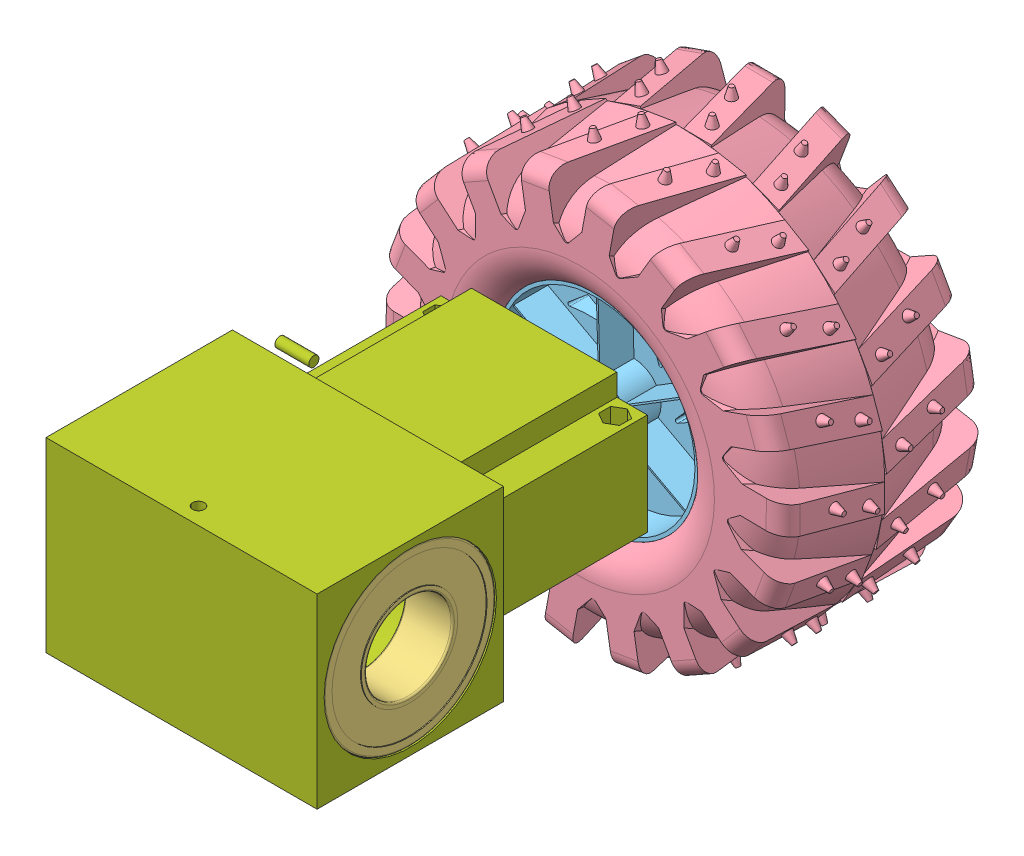
SolidWorks assembly Arm, configuration Default. Lengths in mm.
Overall size (177.35 260.67 181.49).
17 component instances, 13 part files, 22 mates.
Components (placement in the parent):
- Pololu_GearMotor_37Dmm-1: Pololu_GearMotor_37Dmm [Default] at (-21.9765 6.5818 -8.7754) x (0.802354 -0.596848 0.000047) z (-0.000059 0 1) size (51.49 51.49 82.3)
  - Pololu_ShaftGearMotor6mm-1: Pololu_ShaftGearMotor6mm [Default] at (9.8861 24.7007 16.6991) x (0.930815 0.36549 0) z (0 0 1) size (6 6 22)
  - Pololu_GearMotor_37Dmm-1: Pololu_GearMotor_37Dmm [Default] at (5.7082 30.3171 38.6991) x (-0.802354 -0.596848 0) z (0 0 -1) size (36.8 36.8 66.8)
- BallBearing16412RS-1: BallBearing16412RS [Default] at (40.4875 7.4102 -38.9392) x (-0.000059 0.14438 0.989522) z (-1 0 -0.000059) size (50.8 50.8 14.29)
- BallBearing16412RS-2: BallBearing16412RS [Default] at (-24.8068 -116.646 75.0398) x (-0.000012 0.977505 0.210913) z (-1 0 -0.000059) size (50.8 50.8 14.29)
- Wheel-1: Wheel [Default] at (10.2673 32.2355 -37.5744) x (0.772434 0.635095 0.000046) z (0.000059 0 -1) size (126 126 62.61)
  - Tire-1: Tire [Varsayılan] at origin size (126 126 62.61)
  - tire_rim-1: tire_rim [Varsayılan] at (-6.6946 4.5427 -50) size (60 60 50)
- HexWheelAdapter12_6mm-1: HexWheelAdapter12_6mm [Default] at (0.6976 20.5 1.425) x (0.915592 -0.402109 0.000054) z (-0.000059 0 1) size (13.44 15.09 20)
- MotorHolder1-1: MotorHolder1 [Default] at (-39.2999 93.4918 -40.4552) x (-0.000059 0 1) z (-1 0 -0.000059) size (107 55 80)
- SuspensionLeft^Arm-2: SuspensionLeft^Arm [Default] at (43.4552 -26.1865 505.664) x (0.000059 0 -1) z (1 0 0.000059) size (55 192.5 30) (virtual)
- Suspension-1: Suspension [Default] at (-42.1157 47.3123 436.7422) x (-0.000059 0 1) z (-1 0 -0.000059) size (55 192.5 45)
- ShockAbsorber-2: ShockAbsorber [Default] at (42.2636 81.7497 -92.1001) x (-0.438733 0.394039 -0.807618) z (0.898618 0.192408 -0.394291) size (32.16 141.39 32.1) (flexible)
  - ShockBody^ShockAbsorber-2: ShockBody^ShockAbsorber [Default] at (-110.8156 118.4702 -126.402) x (0.898594 0 0.43878) z (-0.43878 0 0.898594) size (22.02 74.55 22) (virtual)
  - Part4^ShockAbsorber-1: Part4^ShockAbsorber [Default] at (-111.2144 107.2476 -126.5968) x (-0.898594 0 -0.43878) z (0.43878 0 -0.898594) size (24 84.5 24) (virtual)
  - SpringAdjuster^ShockAbsorber-1: SpringAdjuster^ShockAbsorber [Default] at (-111.0405 99.3643 -126.5119) x (0.373644 0 -0.927572) z (0.927572 0 0.373644) size (24.5 8.5 24.5) (virtual)
  - Spring^ShockAbsorber-2: Spring^ShockAbsorber [Default] at (-34.7976 -2.4454 -146.0502) x (0 1 0) z (0 0 -1) (virtual)
Mates (geometry in assembly coordinates):
- Concentric21: concentric anti-aligned: circle of Pololu_GearMotor_37Dmm-1/Pololu_GearMotor_37Dmm-1; cylinder of ? through (5.7082 30.3171 38.6991) axis (0 0 1) radius 18.45
- Coincident26: coincident anti-aligned: plane of ?; plane of ? through (-65.7731 59.3921 38.6991) normal (0 0 1)
- Concentric25: concentric aligned: circle of Pololu_GearMotor_37Dmm-1/Pololu_GearMotor_37Dmm-1; circle of ?
- Coincident24: coincident anti-aligned: plane of BallBearing16412RS-1; plane of ? through (26.1682 45.5368 116.1991) normal (0.802354 0.596848 0)
- Coincident25: coincident anti-aligned: plane of BallBearing16412RS-2; plane of ? through (-54.1389 68.0463 -31.6788) normal (-0.802354 -0.596848 0)
- Concentric29: concentric aligned: circle of HexWheelAdapter12_6mm-1; circle of Pololu_GearMotor_37Dmm-1/Pololu_ShaftGearMotor6mm-1
- Coincident27: coincident anti-aligned: plane of HexWheelAdapter12_6mm-1 through (0.6972 20.5 7.925) normal (-0.000059 0 1); plane of Pololu_GearMotor_37Dmm-1/Pololu_ShaftGearMotor6mm-1 through (0.6972 20.5 7.925) normal (0.000059 0 -1)
- Concentric34: concentric anti-aligned: circle of Wheel-1/tire_rim-1; circle of HexWheelAdapter12_6mm-1
- Coincident36: coincident anti-aligned: plane of Wheel-1/tire_rim-1 through (0.6976 20.5 1.425) normal (-0.000059 0 1); plane of HexWheelAdapter12_6mm-1 through (0.6976 20.5 1.425) normal (0.000059 0 -1)
- Parallel6: parallel anti-aligned: plane of Wheel-1/tire_rim-1 through (-2.0321 14.7654 11.4249) normal (-0.079339 0.996848 -0.000005); plane of HexWheelAdapter12_6mm-1 through (-2.2808 14.2441 21.4249) normal (0.079339 -0.996848 0.000005)
- Concentric36: concentric anti-aligned: cylinder of BallBearing16412RS-2 through (-39.0962 27.5 107.4227) axis (1 0 0.000059) radius 25.4; cylinder of MotorHolder1-1 through (-24.8087 27.5 107.4235) axis (-1 0 -0.000059) radius 25.425
- Coincident37: coincident anti-aligned: plane of BallBearing16412RS-2 through (-24.8068 -116.646 75.0398) normal (1 0 0.000059); plane of MotorHolder1-1 through (-24.7999 93.4918 -40.4543) normal (-1 0 -0.000059)
- Concentric37: concentric aligned: cylinder of BallBearing16412RS-1 through (26.1913 27.5 107.4265) axis (1 0 0.000059) radius 25.4; cylinder of MotorHolder1-1 through (26.1913 27.5 107.4265) axis (1 0 0.000059) radius 25.425
- Coincident38: coincident anti-aligned: plane of BallBearing16412RS-1 through (26.2 7.4102 -38.94) normal (-1 0 -0.000059); plane of MotorHolder1-1 through (26.1913 27.5 107.4265) normal (1 0 0.000059)
- Coincident39: coincident anti-aligned: plane of MotorHolder1-1 through (40.7001 0 -40.4504) normal (0 -1 0); plane of assembly through (0 0 0) normal (0 1 0)
- Concentric38: concentric anti-aligned: cylinder of Pololu_GearMotor_37Dmm-1/Pololu_GearMotor_37Dmm-1 through (0.6945 27.5 53.925) axis (0.000059 0 -1) radius 18.4; cylinder of MotorHolder1-1 through (0.6959 27.5 29.925) axis (-0.000059 0 1) radius 18.45
- Concentric39: concentric anti-aligned: cylinder of Pololu_GearMotor_37Dmm-1/Pololu_GearMotor_37Dmm-1 through (0.6963 20.5 23.425) axis (-0.000059 0 1) radius 6; cylinder of MotorHolder1-1 through (0.6956 20.5 34.925) axis (0.000059 0 -1) radius 6
- Coincident40: coincident anti-aligned: plane of Pololu_GearMotor_37Dmm-1/Pololu_GearMotor_37Dmm-1 through (0.6959 27.5 29.925) normal (0.000059 0 -1); plane of MotorHolder1-1 through (-39.3041 93.4918 29.9227) normal (-0.000059 0 1)
- Coincident19: coincident anti-aligned: plane of BallBearing16412RS-1 through (40.4875 7.4102 -38.9392) normal (1 0 0.000059); plane of SuspensionLeft^Arm-2 through (40.4788 27.5 107.4274) normal (-1 0 -0.000059)
- Coincident10: coincident anti-aligned: plane of BallBearing16412RS-2 through (-39.0943 -116.646 75.039) normal (-1 0 -0.000059); plane of Suspension-1 through (-39.0962 27.5 107.4227) normal (1 0 0.000059)
- Concentric57: concentric aligned: cylinder of MotorHolder1-1 through (-8.756 44.45 62.4245) axis (-1 0 -0.000059) radius 1.75; cylinder of ShockAbsorber-2/Part4^ShockAbsorber-1 through (-20.506 44.45 62.4238) axis (-1 0 -0.000059) radius 1.5
- Distance18: distance = 0.75 mm anti-aligned: plane of MotorHolder1-1 through (-19.754 93.4918 27.9238) normal (-1 0 -0.000059); plane of ShockAbsorber-2/Part4^ShockAbsorber-1 through (-20.506 44.45 62.4238) normal (1 0 0.000059)
